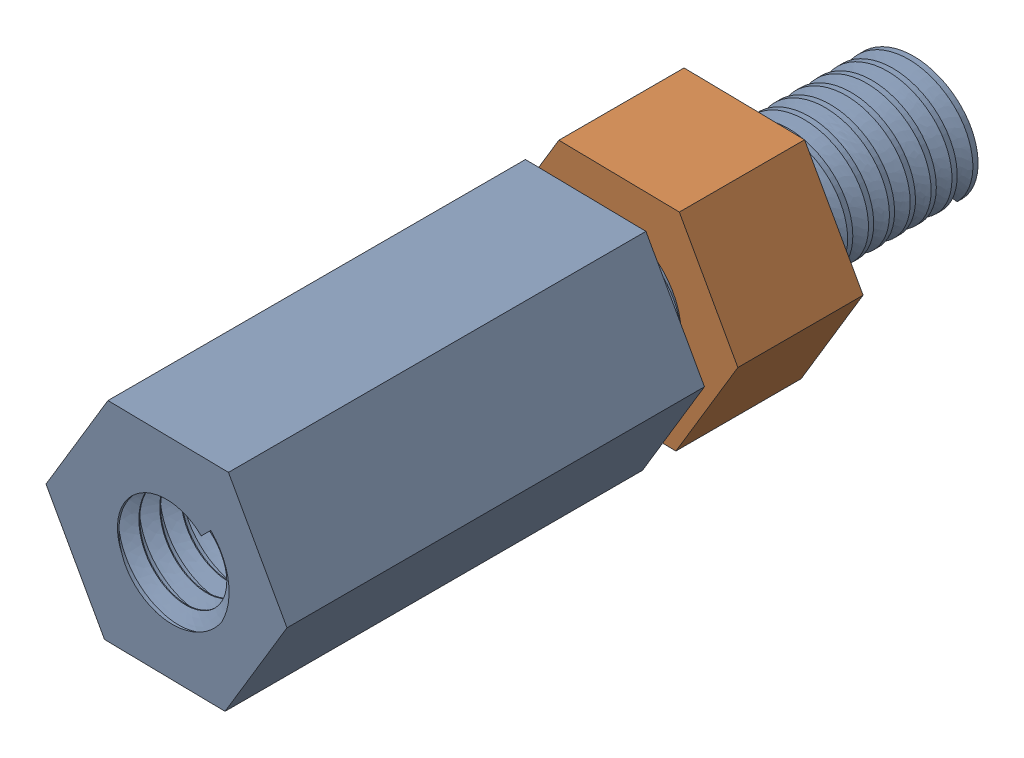
SolidWorks assembly HOLE2, configuration Défaut. Lengths in mm.
Overall size (5.77 5.05 18.25).
2 component instances, 2 part files, 0 mates.
Components (placement in the parent):
- User_Library-Spacer-M3-10mm-1: User_Library-Spacer-M3-10mm [Défaut] at (25.0001 25.0001 0) x (1 0 0) z (0 -1 0) size (5.77 18.25 5.05)
- User_Library-Female_screw_M3-1: User_Library-Female_screw_M3 [Défaut] at (25.0001 25.0001 -3.8) x (1 0 0) z (0 -1 0) size (5.77 3 5.05)
